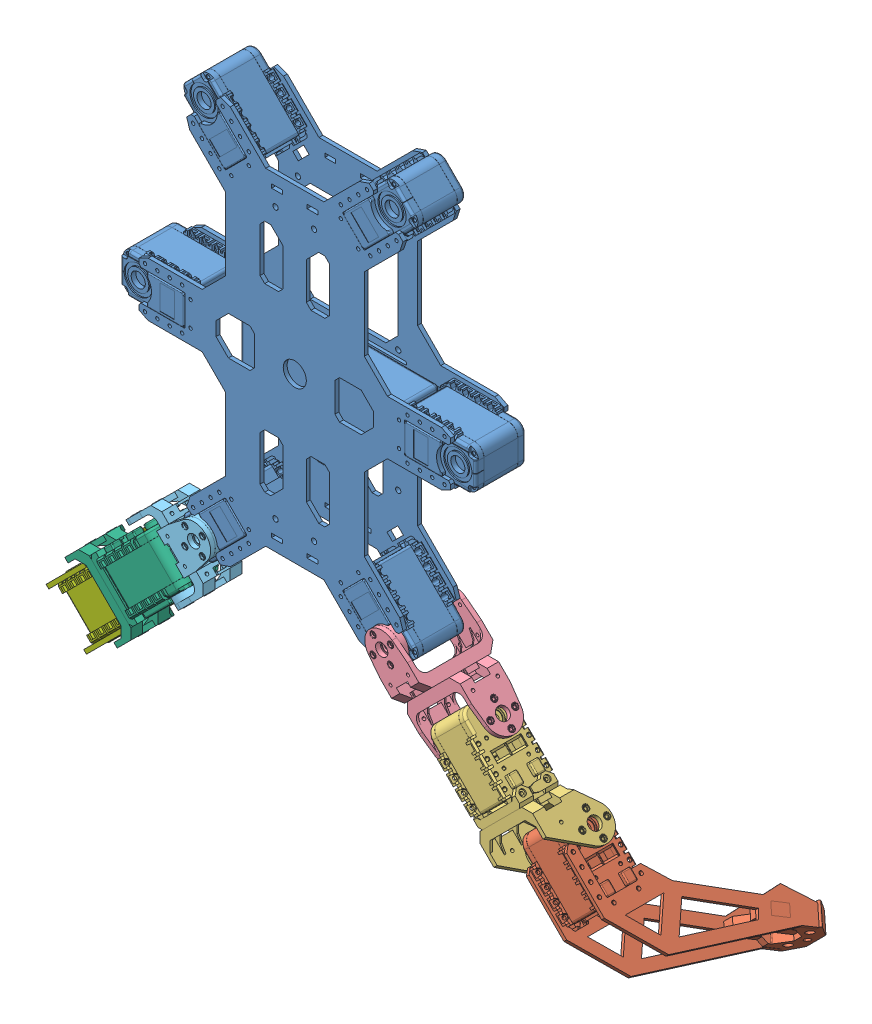
SolidWorks assembly Hexapod, configuration Default. Lengths in mm.
Overall size (460.09 428.8 145.5).
9 component instances, 7 part files, 4 mates.
Components (placement in the parent):
- Main_body-1: Main_body [Default] at origin size (230.08 274.24 38.67)
- Left_Leg-1: Left_Leg [Default] at (60.9101 -121.9101 -2.6) x (-0.707107 -0.707107 0) z (0 0 1) size (49.4 225.94 139)
  - Tibia_left-3: Tibia_left [Default] at (15.2 117.5 -28.8423) x (0 0 1) z (1 0 0) size (117.7 108.98 38.67)
  - Femur_left-3: Femur_left [Default] at (14.2997 53 -14.2997) x (0 0 1) z (1 0 0) size (42.04 87.04 48.5)
  - Coxa_left-3: Coxa_left [Default] at origin size (48.5 75 48.5)
- Right_Leg-1: Right_Leg [Default] at (-60.9101 -121.9101 -2.6) x (-0.707107 0.707107 0) z (0 0 1) size (49.4 225.94 145.5)
  - Coxa_right-1: Coxa_right [Default] at origin size (48.5 75 48.5)
  - Femur_right-1: Femur_right [Default] at (-14.3003 53 -14.2997) x (0 0 -1) z (-1 0 0) size (42.04 87.04 48.5)
  - Tibia_right-1: Tibia_right [Default] at (-15.2 117.5 -34.3423) x (0 0 -1) z (-1 0 0) size (117.7 108.98 38.67)
Mates (geometry in assembly coordinates):
- Parallel1: parallel aligned: plane of Main_body-1 through (156.2424 141.9391 293.4318) normal (-0.707107 0 0.707107); plane of ? through (199.934 132.1191 336.4174) normal (-0.707107 0 0.707107)
- Coincident17: coordinate: point of Main_body-1; point of assembly
- Coincident18: coordinate: unknown of Right_Leg-1/Coxa_right-1
- Coincident19: coordinate: unknown of Left_Leg-1/Coxa_left-3
